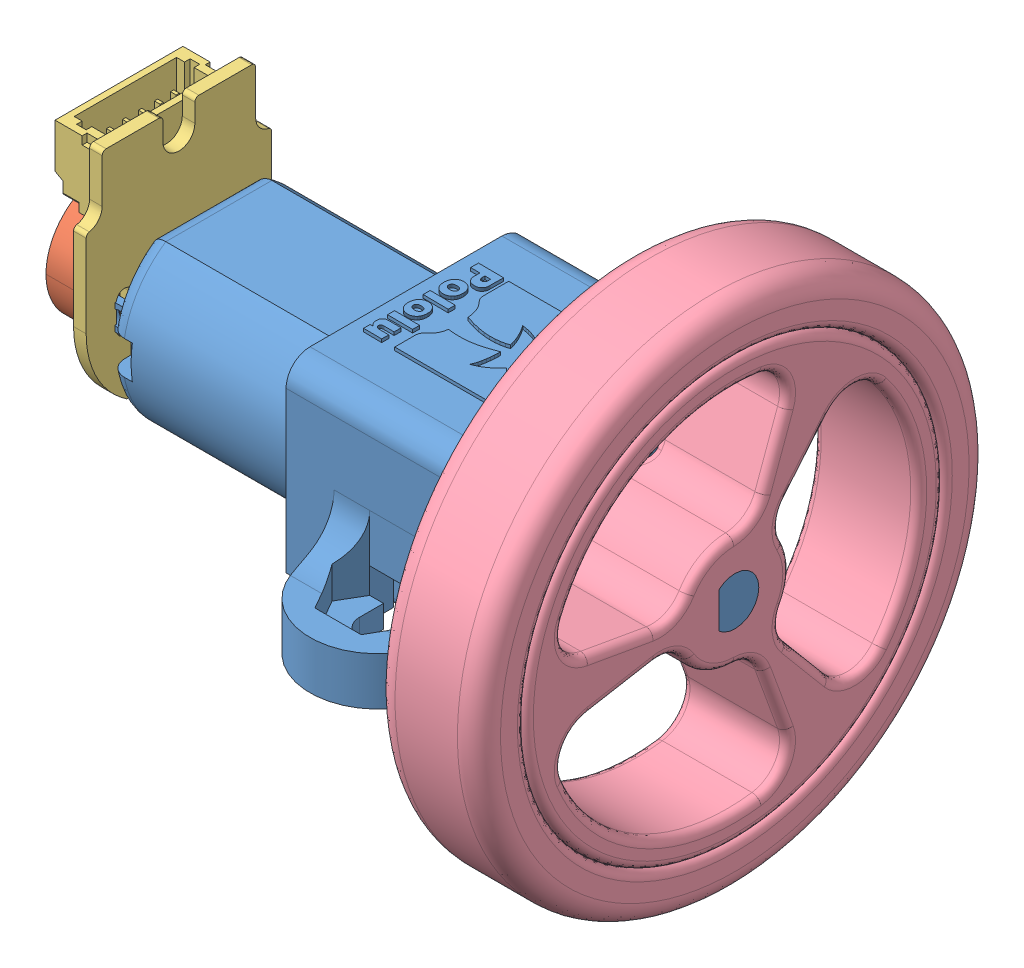
SolidWorks assembly polulu-micromotor-assembly, configuration Default. Lengths in mm.
Overall size (39.27 32 32).
4 component instances, 4 part files, 8 mates.
Components (placement in the parent):
- micro-metal-gearmotor-extended-with-1086-bracket-1: micro-metal-gearmotor-extended-with-1086-bracket [Default] at (-135.5273 31.7211 50.1078) size (39.27 11.71 26.51)
- magnetic-encoder-disc-for-micro-metal-gearmotors-1: magnetic-encoder-disc-for-micro-metal-gearmotors [Default] at (-156.5147 31.7211 50.1078) x (0 0 -1) z (1 0 0) size (7.65 7.65 2)
- magnetic-encoder-with-side-entry-connector-for-micro-metal-gearmotors-1: magnetic-encoder-with-side-entry-connector-for-micro-metal-gearmotors [Default] at (-152.0273 31.7211 50.1078) x (0 0 -1) z (-1 0 0) size (11.6 14.2 3.75)
- pololu-wheel-32x7mm-black-1: pololu-wheel-32x7mm-black [Default] at (-120.5573 31.7211 50.1078) x (0 1 0) z (1 0 0) size (32 32 8.6)
Mates (geometry in assembly coordinates):
- Coincident1: coincident: plane of micro-metal-gearmotor-extended-with-1086-bracket-1 through (-152.0273 31.7211 50.1078) normal (-1 0 0); plane of magnetic-encoder-with-side-entry-connector-for-micro-metal-gearmotors-1 through (-152.0273 31.7211 50.1078) normal (1 0 0)
- Concentric1: concentric: cylinder of micro-metal-gearmotor-extended-with-1086-bracket-1 through (-156.5273 31.7211 50.1078) axis (1 0 0) radius 0.5; cylinder of magnetic-encoder-with-side-entry-connector-for-micro-metal-gearmotors-1 through (-152.8147 31.7211 50.1078) axis (1 0 0) radius 0.8128
- Parallel2: parallel aligned: plane of micro-metal-gearmotor-extended-with-1086-bracket-1 through (-135.5273 26.7212 50.1078) normal (0 -1 0); plane of magnetic-encoder-with-side-entry-connector-for-micro-metal-gearmotors-1 through (-152.8147 26.9211 48.8831) normal (0 -1 0)
- Concentric2: concentric: cylinder of micro-metal-gearmotor-extended-with-1086-bracket-1 through (-156.5273 31.7211 50.1078) axis (1 0 0) radius 0.5; cylinder of magnetic-encoder-disc-for-micro-metal-gearmotors-1 through (-154.5147 31.7211 50.1078) axis (-1 0 0) radius 0.5
- Distance1: distance = 0.5 mm anti-aligned: plane of magnetic-encoder-with-side-entry-connector-for-micro-metal-gearmotors-1 through (-154.0147 29.771 51.7509) normal (-1 0 0); plane of magnetic-encoder-disc-for-micro-metal-gearmotors-1 through (-154.5147 31.7211 50.1078) normal (1 0 0)
- Concentric3: concentric: cylinder of micro-metal-gearmotor-extended-with-1086-bracket-1 through (-116.5273 31.7211 50.1078) axis (-1 0 0) radius 1.5; cylinder of pololu-wheel-32x7mm-black-1 through (-103.7162 31.7211 50.1078) axis (1 0 0) radius 1.5
- Coincident4: coincident: plane of micro-metal-gearmotor-extended-with-1086-bracket-1 through (-116.5273 32.8391 51.1078) normal (0 0 1); plane of pololu-wheel-32x7mm-black-1 through (-103.7162 32.8391 51.1078) normal (0 0 -1)
- Coincident5: coincident aligned: plane of micro-metal-gearmotor-extended-with-1086-bracket-1 through (-117.2573 31.7211 50.1078) normal (1 0 0); plane of pololu-wheel-32x7mm-black-1 through (-95.1162 31.7211 50.1078) normal (1 0 0)
